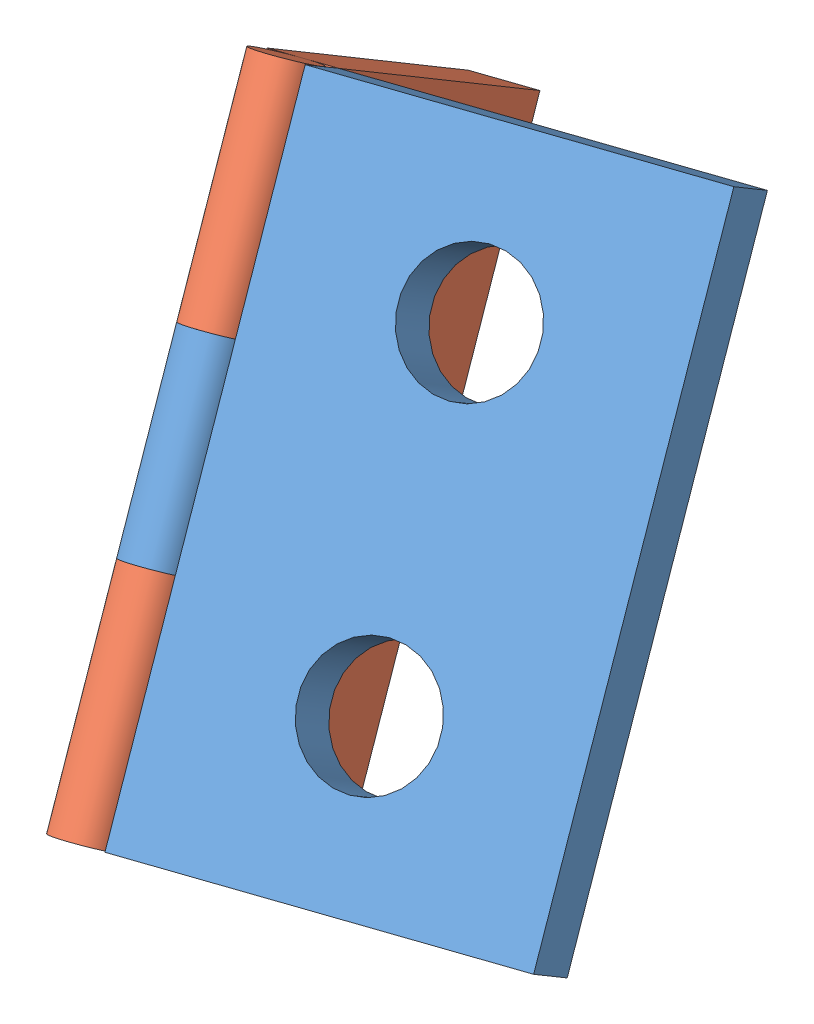
SolidWorks assembly charnière f, configuration Défaut. Lengths in mm.
Overall size (50.34 62.13 55.96).
2 component instances, 2 part files, 3 mates.
Components (placement in the parent):
- charnièer2-1: charnièer2 [Défaut] at (68.0308 -20.5009 -28.8215) x (-0.184624 0.826134 -0.53237) z (0.215686 0.562535 0.798144) size (50 35 5)
- charnièer1-3: charnièer1 [Défaut] at (28.0005 -38.5156 -42.8943) x (-0.184624 0.826134 -0.53237) z (0.95885 0.032532 -0.282043) size (50 35 5)
Mates (geometry in assembly coordinates):
- Coaxiale1: concentric: circle of charnièer2-1; circle of charnièer1-3
- Coïncidente1: coincident: plane of charnièer2-1 through (93.6745 -5.0639 -46.6313) normal (0.184624 -0.826134 0.53237); plane of charnièer1-3 through (56.1718 -27.9819 -69.1897) normal (-0.184624 0.826134 -0.53237)
- Perpendiculaire1: perpendicular: line of charnièer2-1 through (58.7996 20.8058 -55.44) axis (-0.95885 -0.032532 0.282043); line of charnièer1-3 through (23.5636 2.9538 -70.923) axis (0.215686 0.562535 0.798144)
